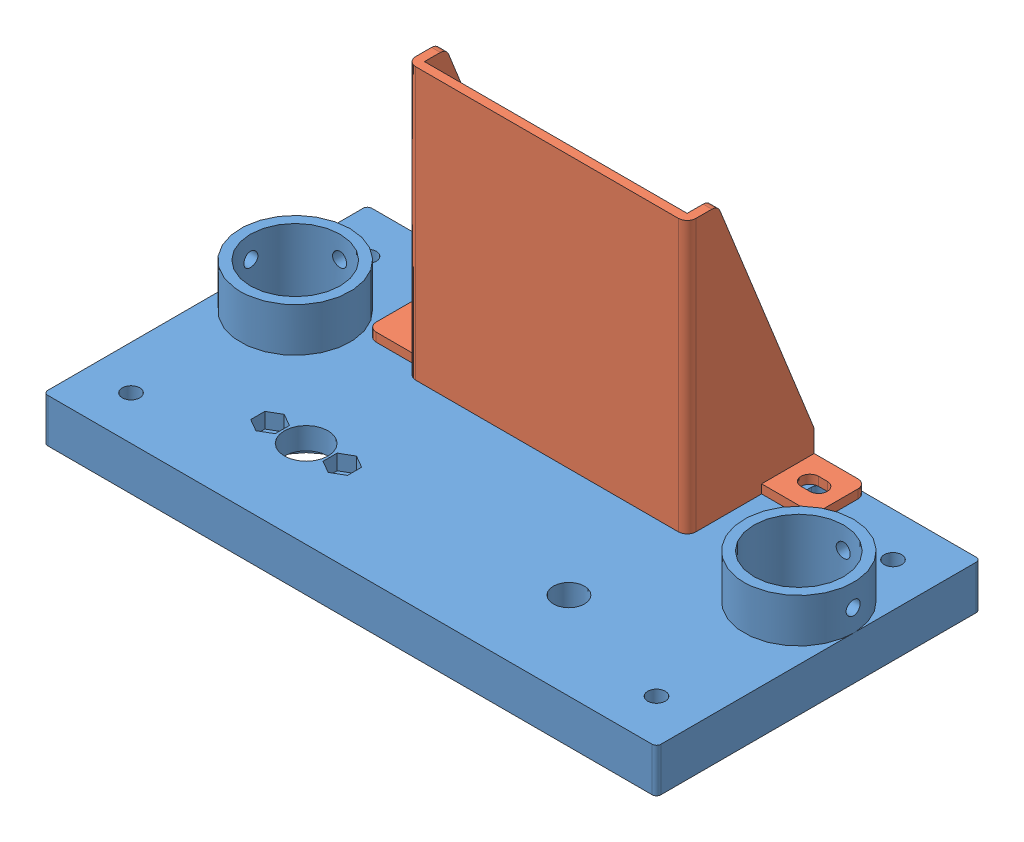
SolidWorks assembly Ensamblaje1, configuration Predeterminado. Lengths in mm.
Overall size (140 72 86.31).
2 component instances, 2 part files, 3 mates.
Components (placement in the parent):
- Base-1: Base [Predeterminado] at (-58.0554 -8.7389 14.5) size (140 20 86.31)
- soporteMotor-1: soporteMotor [Predeterminado] at (-58.0554 1.2611 -22.5) x (-1 0 0) z (0 0 -1) size (88 62 29)
Mates (geometry in assembly coordinates):
- Coincidente1: coincident anti-aligned: plane of Base-1 through (-58.0554 1.2611 14.5) normal (0 1 0); plane of soporteMotor-1 through (-58.0554 1.2611 -22.5) normal (0 -1 0)
- Paralelo1: parallel aligned: plane of soporteMotor-1 through (-58.0554 3.2611 -37) normal (0 0 -1); plane of Base-1 through (-58.0554 -8.7389 -37) normal (0 0 -1)
- Ancho1: width aligned: plane of soporteMotor-1 through (-14.0554 3.2611 -22.5) normal (1 0 0); plane of soporteMotor-1 through (-102.0554 3.2611 -22.5) normal (-1 0 0); plane of Base-1 through (11.9446 1.2611 4.5) normal (1 0 0); plane of Base-1 through (-128.0554 1.2611 4.5) normal (-1 0 0)
